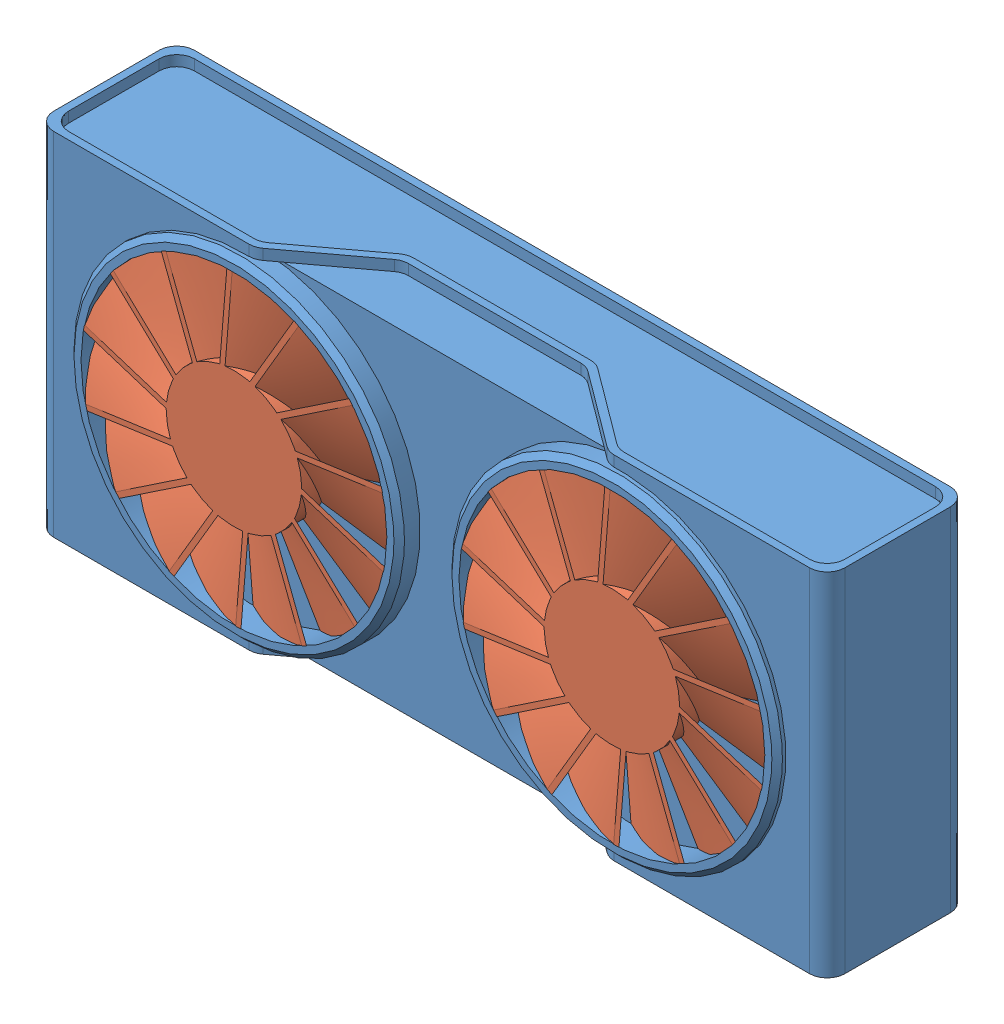
SolidWorks assembly FINAL ASSEMBLY, configuration Default. Lengths in mm.
Overall size (45 20 8.77).
3 component instances, 2 part files, 2 mates.
Components (placement in the parent):
- RTX2060 USB-1: RTX2060 USB [Default] at (3.0608 21.8395 42.9068) size (45 20 8.5)
- fan-1: fan [Default] at (14.8108 31.8395 49.9068) size (17.4 17.4 2.05)
- fan-2: fan [Default] at (36.3108 31.8395 49.9068) size (17.4 17.4 2.05)
Mates (geometry in assembly coordinates):
- Coincident2: coincident anti-aligned: circle of RTX2060 USB-1; circle of fan-1
- Coincident3: coincident anti-aligned: circle of RTX2060 USB-1; circle of fan-2
